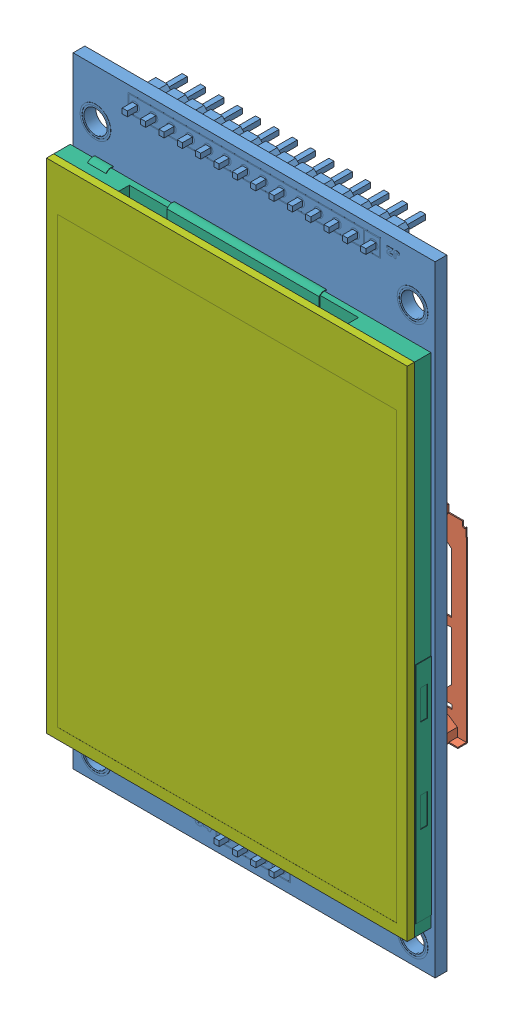
SolidWorks assembly 2.8 TFT Module_mod2, configuration Default. Lengths in mm.
Overall size (50.19 85.9 10.62).
15 component instances, 7 part files, 3 mates.
Components (placement in the parent):
- 2.8 TFT Module.stp-1: 2.8 TFT Module.stp [Default] at origin size (50.19 85.9 11.99)
  - 2.8 LCD TFT Module - Without Glass.stp-1: 2.8 LCD TFT Module - Without Glass.stp [Default] at origin size (50.14 85.9 10.67)
  - 5035000993.stp-1: 5035000993.stp [Default] at (3.5564 -3.3047 -2.85) x (0 1 0) z (0 0 -1) size (28.6 21.52 2.95)
  - 0603 Resistor.stp-1: 0603 Resistor.stp [Default] at (-2.2311 -3.165 0.0025) x (-1 0 0) z (0 0 -1) size (1.6 0.85 0.56)
  - 0603 Capacitor.stp-1: 0603 Capacitor.stp [Default] at (-14.5217 25.6289 0.0025) x (1 0 0) z (0 0 -1) size (1.6 0.84 0.84)
  - 0603 Capacitor.stp-2: 0603 Capacitor.stp [Default] at (-2.484 19.738 0.0025) x (-1 0 0) z (0 0 -1) size (1.6 0.84 0.84)
  - 0603 Resistor.stp-2: 0603 Resistor.stp [Default] at (-3.8795 -4.7617 0.0025) x (1 0 0) z (0 0 -1) size (1.6 0.85 0.56)
  - 0603 Resistor.stp-3: 0603 Resistor.stp [Default] at (-2.3355 -0.9936 0.0025) x (-1 0 0) z (0 0 -1) size (1.6 0.85 0.56)
  - 0603 Resistor.stp-4: 0603 Resistor.stp [Default] at (-12.9341 26.6747 0.0025) x (-1 0 0) z (0 0 -1) size (1.6 0.85 0.56)
  - 0603 Resistor.stp-5: 0603 Resistor.stp [Default] at (4.5338 19.5922 0.0025) x (-1 0 0) z (0 0 -1) size (1.6 0.85 0.56)
  - 0603 Resistor.stp-6: 0603 Resistor.stp [Default] at (4.3803 26.5372 0.0025) x (-1 0 0) z (0 0 -1) size (1.6 0.85 0.56)
  - SOT23-3.stp-1: SOT23-3.stp [Default] at (3.6167 23.9432 0.105) x (0.003406 0.999994 0) z (0 0 -1) size (2.9 3.01 1.23)
  - SOT23-3.stp-2: SOT23-3.stp [Default] at (-3.3735 23.944 0.105) x (0.999985 -0.005499 0) z (0 0 -1) size (2.9 3.01 1.23)
  - 2.8in TFT(Without Glass)- Tucked Cable.stp-1: 2.8in TFT(Without Glass)- Tucked Cable.stp [Default] at (-0.0571 -2.2987 1.6256) x (-1 0 0) z (0 0 1) size (50.11 69.48 2.83)
- GLASS-1: GLASS [Default] at (24.922 -36.8028 4.3434) x (-1 0 0) z (0 1 0) size (49.96 1 69.01)
Mates (geometry in assembly coordinates):
- Coincident3: coincident anti-aligned: plane of 2.8 TFT Module.stp-1/2.8in TFT(Without Glass)- Tucked Cable.stp-1 through (-0.0571 -2.2987 4.3434) normal (0 0 1); plane of GLASS-1 through (24.922 -36.8028 4.3434) normal (0 0 -1)
- Coincident4: coincident aligned: plane of 2.8 TFT Module.stp-1/2.8in TFT(Without Glass)- Tucked Cable.stp-1 through (-25.038 -36.8046 4.3434) normal (-1 0 0); plane of GLASS-1 through (-25.038 -36.8028 5.3434) normal (-1 0 0)
- Coincident5: coincident aligned: plane of 2.8 TFT Module.stp-1/2.8in TFT(Without Glass)- Tucked Cable.stp-1 through (-25.038 32.2072 4.3434) normal (0 1 0); plane of GLASS-1 through (24.922 32.2072 5.3434) normal (0 1 0)
